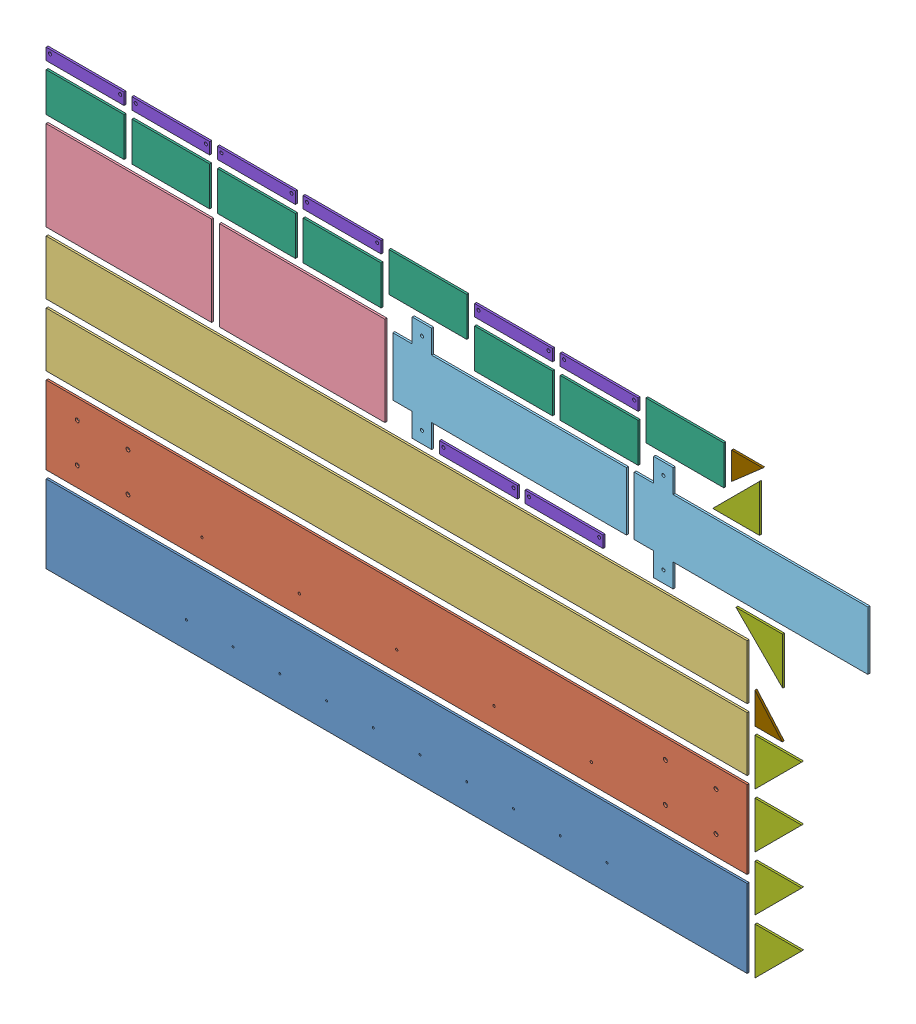
SolidWorks assembly Nesting(5mm), configuration Layout1[Steel_5mm_Qnty1]. Lengths in mm.
Overall size (2400 1200 5).
32 component instances, 9 part files, 0 mates.
Components (placement in the parent):
- Y_Plate_3-1: Y_Plate_3 [Default] at (920 120 0) x (0 -1 0) z (0 0 -1) size (200 1800 5)
- Y_Plate_1-1: Y_Plate_1 [Default] at (920 340 0) x (0 -1 0) z (0 0 -1) size (200 1800 5)
- Y_Plate_2-1: Y_Plate_2 [Default] at (920 530 0) x (0 -1 0) z (0 0 -1) size (140 1800 5)
- Y_Plate_2-2: Y_Plate_2 [Default] at (920 690 0) x (0 -1 0) z (0 0 -1) size (140 1800 5)
- Z_Plate_2-1: Z_Plate_2 [Default] at (237.5 895 0) x (0 -1 0) z (0 0 -1) size (230 425 5)
- Z_Plate_2-2: Z_Plate_2 [Default] at (682.5 895 0) x (0 -1 0) z (0 0 -1) size (230 425 5)
- Z_Plate_1-1: Z_Plate_1 [Default] at (1210 915 0) x (0 1 0) z (0 0 -1) size (270 600 5)
- Z_Plate_1-2: Z_Plate_1 [Default] at (1830 915 0) x (0 1 0) z (0 0 -1) size (270 600 5)
- C Covering 1-1: C Covering 1 [Default] at (120 1080 0) x (1 0 0) z (0 0 -1) size (200 100 5)
- C Covering 1-2: C Covering 1 [Default] at (340 1080 0) x (1 0 0) z (0 0 -1) size (200 100 5)
- C Covering 1-3: C Covering 1 [Default] at (560 1080 0) x (1 0 0) z (0 0 -1) size (200 100 5)
- C Covering 1-4: C Covering 1 [Default] at (780 1080 0) x (1 0 0) z (0 0 -1) size (200 100 5)
- C Covering 1-5: C Covering 1 [Default] at (1000 1120 0) x (1 0 0) z (0 0 -1) size (200 100 5)
- C Covering 1-6: C Covering 1 [Default] at (1220 1060 0) x (1 0 0) z (0 0 -1) size (200 100 5)
- C Covering 1-7: C Covering 1 [Default] at (1440 1060 0) x (1 0 0) z (0 0 -1) size (200 100 5)
- C Covering 1-8: C Covering 1 [Default] at (1660 1120 0) x (1 0 0) z (0 0 -1) size (200 100 5)
- Motor Extension Rib-1: Motor Extension Rib [Default] at (1851.5147 1010 0) x (-1 0 0) z (0 0 -1) size (120 120 5)
- Motor Extension Rib-2: Motor Extension Rib [Default] at (1911.2132 820 0) x (0 -1 0) z (0 0 -1) size (120 120 5)
- Motor Extension Rib-3: Motor Extension Rib [Default] at (1840 140 0) x (1 0 0) z (0 0 -1) size (120 120 5)
- Motor Extension Rib-4: Motor Extension Rib [Default] at (1840 280 0) x (1 0 0) z (0 0 -1) size (120 120 5)
- Motor Extension Rib-5: Motor Extension Rib [Default] at (1840 420 0) x (1 0 0) z (0 0 -1) size (120 120 5)
- Motor Extension Rib-6: Motor Extension Rib [Default] at (1840 560 0) x (1 0 0) z (0 0 -1) size (120 120 5)
- C Covering 2-1: C Covering 2 [Default] at (120 1165 0) x (1 0 0) z (0 0 -1) size (200 30 5)
- C Covering 2-2: C Covering 2 [Default] at (340 1165 0) x (1 0 0) z (0 0 -1) size (200 30 5)
- C Covering 2-3: C Covering 2 [Default] at (560 1165 0) x (1 0 0) z (0 0 -1) size (200 30 5)
- C Covering 2-4: C Covering 2 [Default] at (780 1165 0) x (1 0 0) z (0 0 -1) size (200 30 5)
- C Covering 2-5: C Covering 2 [Default] at (1130 795 0) x (1 0 0) z (0 0 -1) size (200 30 5)
- C Covering 2-6: C Covering 2 [Default] at (1220 1145 0) x (1 0 0) z (0 0 -1) size (200 30 5)
- C Covering 2-7: C Covering 2 [Default] at (1350 795 0) x (1 0 0) z (0 0 -1) size (200 30 5)
- C Covering 2-8: C Covering 2 [Default] at (1440 1145 0) x (1 0 0) z (0 0 -1) size (200 30 5)
- Rib-1: Rib [Default] at (1780 1164 0) x (0 0 -1) z (-1 0 0) size (5 70 80)
- Rib-2: Rib [Default] at (1840 580 0) x (0 0 -1) z (0 -1 0) size (5 70 80)
